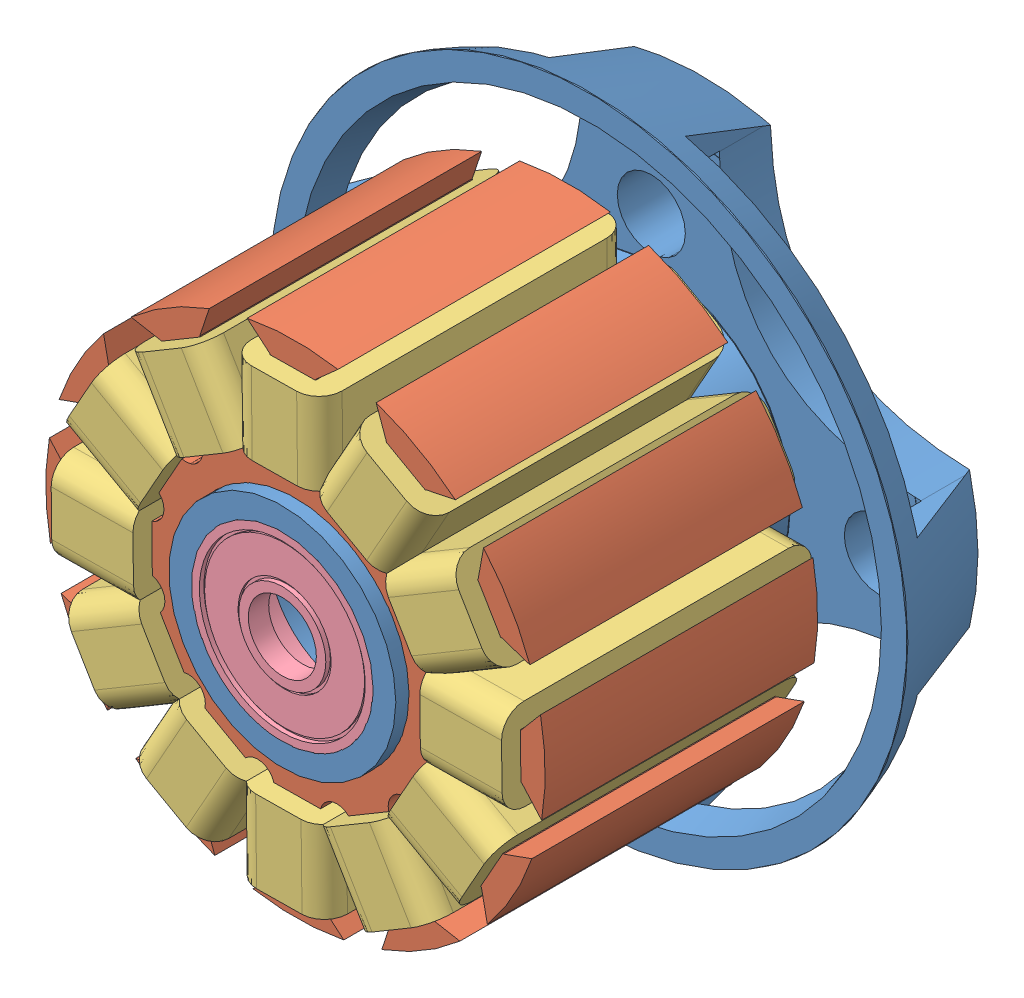
SolidWorks assembly motor_stator, configuration Default. Lengths in mm.
Overall size (28 28 18.85).
16 component instances, 4 part files, 8 mates.
Components (placement in the parent):
- base-1: base [Default] at (10.5479 11.9817 13.9786) size (28 28 18.5)
- armature-1: armature [Default] at (10.5479 11.9817 19.8988) x (0.999929 0.011943 0) z (0 0 1) size (22 22 12)
- wire-1: wire [Default] at (10.4725 18.2982 25.8988) x (0.999929 0.011943 0) z (0 0 1) size (4 3.6 13.66)
- wire-2: wire [Default] at (13.6409 17.4897 25.8988) x (0.871935 -0.489621 0) z (0 0 1) size (4 3.6 13.66)
- wire-3: wire [Default] at (15.9805 15.2053 25.8988) x (0.510307 -0.859992 0) z (0 0 1) size (4 3.6 13.66)
- wire-4: wire [Default] at (16.8645 12.0571 25.8988) x (0.011943 -0.999929 0) z (0 0 1) size (4 3.6 13.66)
- wire-5: wire [Default] at (16.056 8.8887 25.8988) x (-0.489621 -0.871935 0) z (0 0 1) size (4 3.6 13.66)
- wire-6: wire [Default] at (13.7716 6.5491 25.8988) x (-0.859992 -0.510307 0) z (0 0 1) size (4 3.6 13.66)
- wire-7: wire [Default] at (10.6234 5.6651 25.8988) x (-0.999929 -0.011943 0) z (0 0 1) size (4 3.6 13.66)
- wire-8: wire [Default] at (7.455 6.4736 25.8988) x (-0.871935 0.489621 0) z (0 0 1) size (4 3.6 13.66)
- wire-9: wire [Default] at (5.1153 8.758 25.8988) x (-0.510307 0.859992 0) z (0 0 1) size (4 3.6 13.66)
- wire-10: wire [Default] at (4.2314 11.9062 25.8988) x (-0.011943 0.999929 0) z (0 0 1) size (4 3.6 13.66)
- wire-11: wire [Default] at (5.0399 15.0746 25.8988) x (0.489621 0.871935 0) z (0 0 1) size (4 3.6 13.66)
- wire-12: wire [Default] at (7.3243 17.4143 25.8988) x (0.859992 0.510307 0) z (0 0 1) size (4 3.6 13.66)
- bearing-1: bearing [Default] at (10.5479 11.9817 29.4786) x (0.999972 -0.007521 0) z (-0.007521 -0.999972 0) size (8 3 8)
- bearing-2: bearing [Default] at (10.5479 11.9817 16.8786) x (-0.923728 -0.383049 0) z (0.383049 -0.923728 0) size (8 3 8)
Mates (geometry in assembly coordinates):
- Concentric1: concentric: cylinder of assembly; cylinder of assembly; cylinder of base-1 through (10.5479 11.9817 18.9786) axis (0 0 1) radius 5; cylinder of armature-1 through (10.5479 11.9817 19.8988) axis (0 0 1) radius 5
- Distance1: distance = 0.5798 mm: plane of assembly; plane of assembly; plane of armature-1 through (10.5479 11.9817 31.8988) normal (0 0 1); plane of base-1 through (10.5479 11.9817 32.4786) normal (0 0 1)
- Coincident3: coincident: plane of assembly; plane of assembly; plane of armature-1 through (11.5479 11.9936 31.8988) normal (0.999929 0.011943 0); plane of wire-1 through (11.4294 21.9099 19.8988) normal (-0.999929 -0.011943 0)
- Coincident4: coincident: plane of assembly; plane of assembly; plane of armature-1 through (10.5479 11.9817 31.8988) normal (0 0 1); plane of wire-1 through (9.4296 21.886 31.8988) normal (0 0 -1)
- Concentric2: concentric: cylinder of assembly; cylinder of assembly; cylinder of base-1 through (10.5479 11.9817 9.9786) axis (0 0 1) radius 4; cylinder of bearing-1 through (10.5479 11.9817 32.4786) axis (0 0 -1) radius 4
- Coincident5: coincident: plane of assembly; plane of assembly; plane of base-1 through (10.5479 11.9817 32.4786) normal (0 0 1); plane of bearing-1 through (10.5479 11.9817 32.4786) normal (0 0 1)
- Concentric3: concentric: cylinder of assembly; cylinder of assembly; cylinder of base-1 through (10.5479 11.9817 9.9786) axis (0 0 1) radius 4; cylinder of bearing-2 through (10.5479 11.9817 13.8786) axis (0 0 1) radius 4
- Coincident6: coincident: plane of assembly; plane of assembly; plane of base-1 through (10.5479 11.9817 13.9786) normal (0 0 -1); plane of bearing-2 through (10.5479 11.9817 13.9786) normal (0 0 -1)
